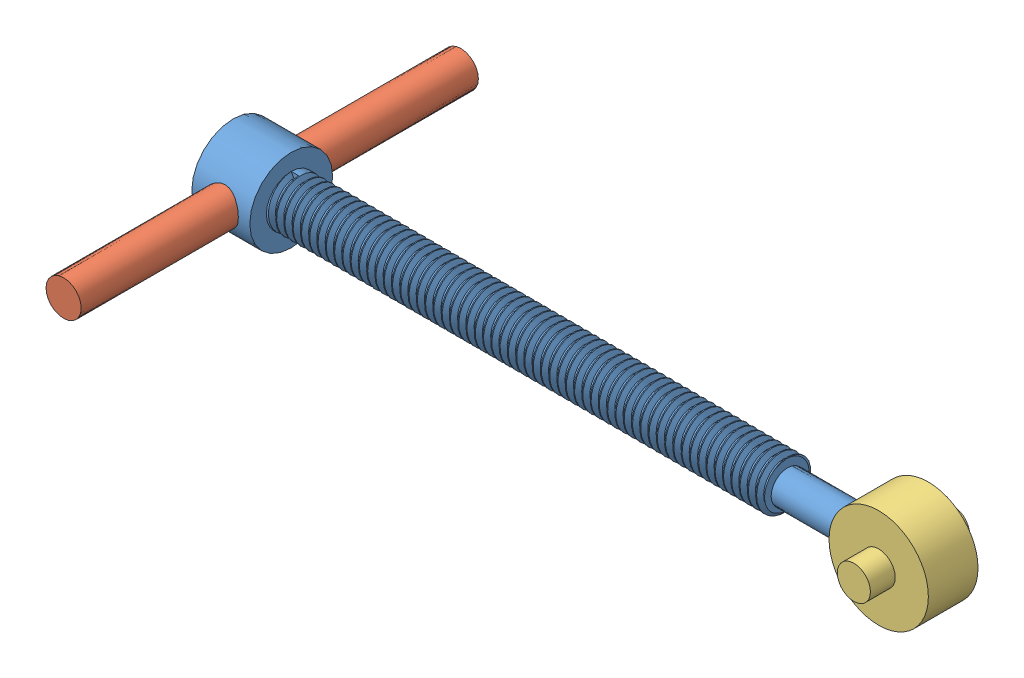
SolidWorks assembly Assem1, configuration Default. Lengths in mm.
Overall size (138.13 19.05 76.2).
3 component instances, 3 part files, 6 mates.
Components (placement in the parent):
- Part7ASS2-1: Part7ASS2 [Default] at (-9.4076 64.5407 97.2677) size (128.6 15.9 15.9)
- Handle-3: Handle [Default] at (-3.845 64.5407 97.2677) size (6.76 6.76 76.2)
- Hinge-1: Hinge [Default] at (119.1926 64.5407 97.2677) size (19.05 19.05 19.05)
Mates (geometry in assembly coordinates):
- Concentric3: concentric anti-aligned: cylinder of Part7ASS2-1 through (-3.845 64.5407 89.3175) axis (0 0 1) radius 2.4474; cylinder of Handle-3 through (-3.845 64.5407 135.3677) axis (0 0 -1) radius 3.3782
- Coincident2: coincident aligned: plane of Part7ASS2-1 through (-9.4076 64.5407 97.2677) normal (0 0 1); plane of Handle-3 through (-3.845 64.5407 97.2677) normal (0 0 1)
- Concentric4: concentric anti-aligned: cylinder of Part7ASS2-1 through (-9.4076 64.5407 97.2677) axis (-1 0 0) radius 3.175; cylinder of Hinge-1 through (109.6676 64.5407 97.2677) axis (1 0 0) radius 3.175
- Coincident3: coincident aligned: plane of Part7ASS2-1 through (119.1926 64.5407 97.2677) normal (1 0 0); circle of Hinge-1
- Coincident4: coincident aligned: plane of Part7ASS2-1 through (-9.4076 64.5407 97.2677) normal (0 0 1); plane of Hinge-1 through (119.1926 64.5407 97.2677) normal (0 0 1)
- Coincident5: coincident aligned: plane of Part7ASS2-1 through (-9.4076 64.5407 97.2677) normal (0 0 1); plane of Hinge-1 through (119.1926 64.5407 97.2677) normal (0 0 1)
